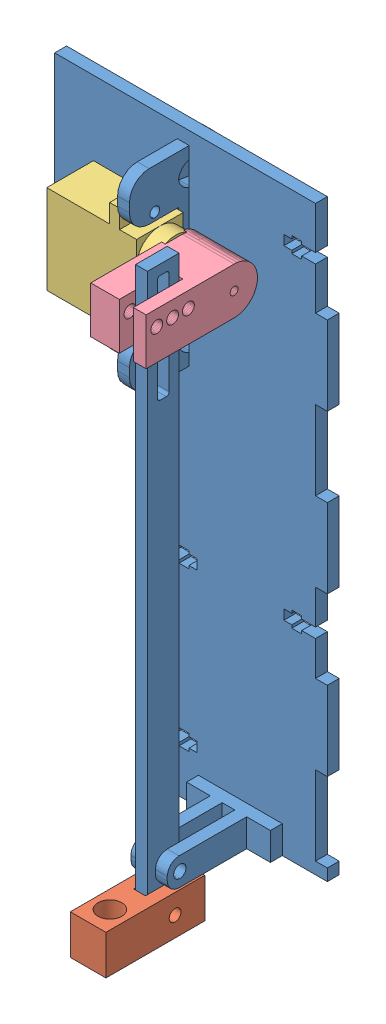
SolidWorks assembly LASER ASSEMBLY, configuration Default. Lengths in mm.
Overall size (68.96 157.53 45.5).
4 component instances, 4 part files, 6 mates.
Components (placement in the parent):
- Master-1: Master [Default] at (-16.8137 19.4204 -115.5225) size (68.96 156.03 32)
- Laser_Holder-1: Laser_Holder [Default] at (-16.7137 -75.5796 36.5776) x (1 0 0) z (0 -1 -0.000011) size (9 25 10)
- Servo-1: Servo [Default] at (-39.8637 44.7351 19.1252) x (0 -1 -0.00019) z (0 -0.00019 1) size (31.9 29.9 11.8)
- hornsleeve-1: hornsleeve [Default] at (-25.4388 55.3835 59.5234) x (0 0.000076 -1) z (0 -1 -0.000076) size (28.16 14 11.8)
Mates (geometry in assembly coordinates):
- Concentric1: concentric aligned: circle of Master-1; circle of Laser_Holder-1
- Coincident1: coincident anti-aligned: plane of Master-1 through (-15.2137 -11.5796 19.5775) normal (1 0 0); plane of Laser_Holder-1 through (-15.2137 -85.5796 36.5775) normal (-1 0 0)
- Concentric2: concentric aligned: circle of Master-1; circle of Servo-1
- Coincident2: coincident anti-aligned: plane of Master-1 through (-32.8137 44.4497 15.1666) normal (-1 0 0); plane of Servo-1 through (-32.8137 58.3851 19.1278) normal (1 0 0)
- Coincident3: coincident anti-aligned: plane of Master-1 through (-18.2137 -11.5796 19.5775) normal (-1 0 0); plane of hornsleeve-1 through (-18.2137 55.3835 59.5234) normal (1 0 0)
- Parallel2: parallel anti-aligned: plane of Master-1 through (-15.2137 -11.5796 19.5775) normal (1 0 0); plane of hornsleeve-1 through (-14.6637 43.5345 39.6847) normal (-1 0 0)
